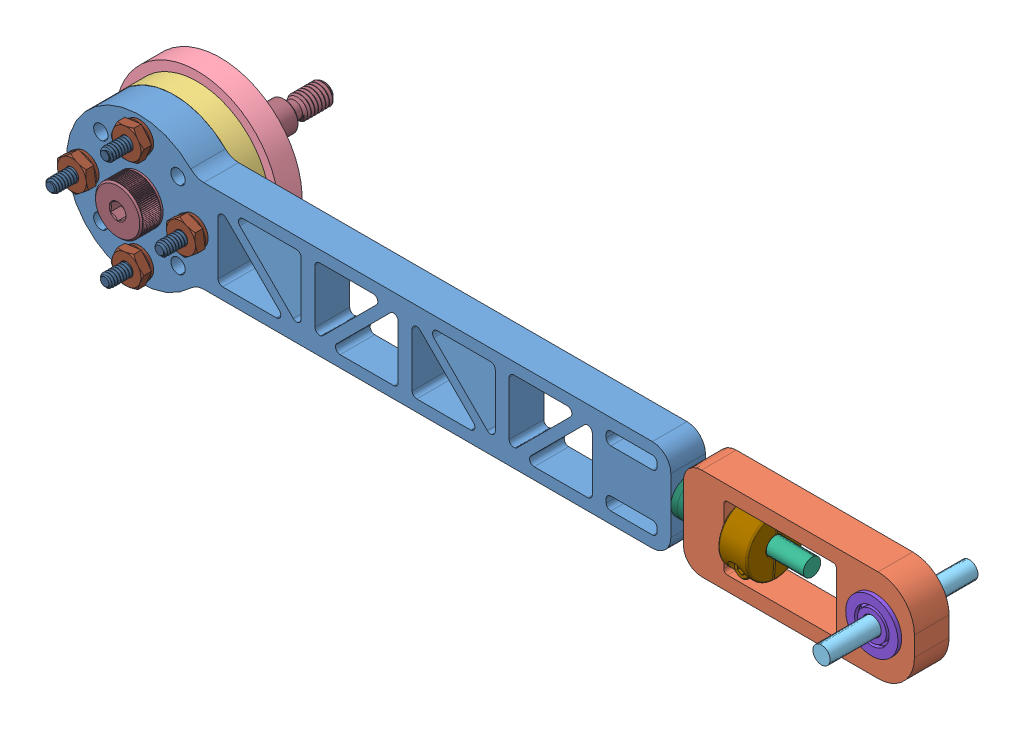
SolidWorks assembly A_5_000, configuration Default. Lengths in mm.
Overall size (235.5 45 66.17).
30 component instances, 15 part files, 41 mates.
Components (placement in the parent):
- A_5_001-1: A_5_001 [Default] at (-75.025 12.7 0) size (166.05 40 9.53)
- A_5_002-1: A_5_002 [Default] at (1.4544 0 0) size (63.5 25.4 9.53)
- A_5_003-1: A_5_003 [Default] at (-148.05 12.7 -6.35) size (40 40 6.35)
- A_5_004-1: A_5_004 [Default] at (-148.05 12.7 -6.35) x (1 0 0) z (0 0 -1) size (45 45 6.35)
- shaft-1: shaft [Default] at (54.2575 12.7 -16.2686) x (0.996155 -0.087603 0) z (0 0 1) size (4.76 4.76 40.64)
- shaft_2-1: shaft_2 [Default] at (-23.5795 12.7 4.7625) x (0 0.971236 0.23812) z (1 0 0) size (4.76 4.76 55.63)
- 2938T280-1: 2938T280 [2938T28] at (14.1481 12.7 4.7625) x (0 0.795039 -0.606559) z (0 0.606559 0.795039) size (11.11 12.7 11.11)
- 57155K302-1: 57155K302 [57155K302] at (54.2575 12.7 0.9684) x (0.999308 -0.037205 0) z (0 0 1) size (14.35 14.35 3.97)
- 57155K302-2: 57155K302 [57155K302] at (54.2575 12.7 8.5566) x (-0.923728 -0.383049 0) z (0 0 -1) size (14.35 14.35 3.97)
- 6157K310-1: 6157K310 [6157K31] at (18.1169 12.7 4.7625) x (0 -0.08236 -0.996603) z (-1 0 0) size (15.88 15.89 7.98)
- 92210A155-1: 92210A155 [92210A155] at (-148.05 27.7 -12.7) x (1 0 0) z (0 0 -1) size (7.8 7.8 32.26)
- 95170A355-1: 95170A355 [95170A355] at (-148.05 27.7 9.525) x (-0.141785 0.989897 0) z (0.989897 0.141785 0) size (8.33 3.94 9.17)
- 92373A215-1: 92373A215 [92373A215] at (-137.4434 23.3066 -3.175) size (4.08 4.11 19.05)
- 92981A206-1: 92981A206 [92981A206] at (-148.05 12.7 15.525) size (13 13 57.56)
- 98055A114-1: 98055A114 [Default] at (-148.05 12.7 -13.2) x (-0.853776 0.520641 0) z (0 0 1) size (14 14 0.5)
- 98055A114-4: 98055A114 [Default] at (-148.05 12.7 -13.7) x (0.553514 -0.83284 0) z (0 0 1) size (14 14 0.5)
- 98055A114-3: 98055A114 [Default] at (-148.05 12.7 -14.2) x (-0.496071 -0.868282 0) z (0 0 1) size (14 14 0.5)
- 98055A114-6: 98055A114 [Default] at (-148.05 12.7 -14.7) x (0.941927 -0.335817 0) z (0 0 1) size (14 14 0.5)
- 98055A114-5: 98055A114 [Default] at (-148.05 12.7 -15.2) x (0.942593 0.333943 0) z (0 0 1) size (14 14 0.5)
- 92373A215-5: 92373A215 [92373A215] at (-158.6566 23.3066 -3.175) x (0 1 0) z (0 0 1) size (4.08 4.11 19.05)
- 92373A215-6: 92373A215 [92373A215] at (-158.6566 2.0934 -3.175) x (-1 0 0) z (0 0 1) size (4.08 4.11 19.05)
- 92373A215-7: 92373A215 [92373A215] at (-137.4434 2.0934 -3.175) x (0 -1 0) z (0 0 1) size (4.08 4.11 19.05)
- 95170A355-2: 95170A355 [95170A355] at (-163.05 12.7 9.525) x (-0.989897 -0.141785 0) z (-0.141785 0.989897 0) size (8.33 3.94 9.17)
- 95170A355-3: 95170A355 [95170A355] at (-148.05 -2.3 9.525) x (0.141785 -0.989897 0) z (-0.989897 -0.141785 0) size (8.33 3.94 9.17)
- 95170A355-4: 95170A355 [95170A355] at (-133.05 12.7 9.525) x (0.989897 0.141785 0) z (0.141785 -0.989897 0) size (8.33 3.94 9.17)
- 92210A155-5: 92210A155 [92210A155] at (-163.05 12.7 -12.7) x (0 1 0) z (0 0 -1) size (7.8 7.8 32.26)
- 92210A155-6: 92210A155 [92210A155] at (-148.05 -2.3 -12.7) x (-1 0 0) z (0 0 -1) size (7.8 7.8 32.26)
- 92210A155-7: 92210A155 [92210A155] at (-133.05 12.7 -12.7) x (0 -1 0) z (0 0 -1) size (7.8 7.8 32.26)
- 90183A315-1: 90183A315 [90183A315] at (-0.2728 12.7 4.7625) x (0 0.636481 -0.771293) z (1 0 0) size (9.53 9.53 1.73)
- 90183A315-2: 90183A315 [90183A315] at (1.4544 12.7 4.7625) x (0 0 -1) z (1 0 0) size (9.53 9.53 1.73)
Mates (geometry in assembly coordinates):
- Concentric1: concentric anti-aligned: cylinder of A_5_002-1 through (64.9554 12.7 4.7625) axis (-1 0 0) radius 3.9751; cylinder of 2938T280-1 through (1.4482 12.7 4.7625) axis (1 0 0) radius 3.9751
- Coincident1: coincident anti-aligned: plane of A_5_002-1 through (12.5606 3.95 0) normal (1 0 0); plane of 2938T280-1 through (12.5606 12.7 4.7625) normal (-1 0 0)
- Concentric2: concentric aligned: cylinder of A_5_002-1 through (54.2575 12.7 0) axis (0 0 1) radius 6.35; cylinder of 57155K302-1 through (54.2575 12.7 2.9527) axis (0 0 1) radius 6.35
- Coincident2: coincident aligned: plane of A_5_002-1; circle of 57155K302-1
- Concentric3: concentric anti-aligned: cylinder of A_5_002-1 through (54.2575 12.7 0) axis (0 0 1) radius 6.35; cylinder of 57155K302-2 through (54.2575 12.7 6.5723) axis (0 0 -1) radius 6.35
- Coincident3: coincident aligned: plane of A_5_002-1; circle of 57155K302-2
- Concentric4: concentric aligned: cylinder of 57155K302-2 through (54.2575 12.7 6.5723) axis (0 0 -1) radius 2.3813; cylinder of shaft-1 through (54.2575 12.7 24.3714) axis (0 0 -1) radius 2.3813
- Concentric5: concentric anti-aligned: cylinder of 2938T280-1 through (1.4482 12.7 4.7625) axis (1 0 0) radius 2.394; cylinder of shaft_2-1 through (32.0465 12.7 4.7625) axis (-1 0 0) radius 2.3813
- Concentric7: concentric anti-aligned: cylinder of A_5_001-1 through (-168.051 12.7 4.7625) axis (1 0 0) radius 2.3813; cylinder of shaft_2-1 through (32.0465 12.7 4.7625) axis (-1 0 0) radius 2.3813
- Concentric8: concentric anti-aligned: cylinder of shaft_2-1 through (32.0465 12.7 4.7625) axis (-1 0 0) radius 2.3813; cylinder of 6157K310-1 through (14.1481 12.7 4.7625) axis (1 0 0) radius 2.3813
- Coincident4: coincident anti-aligned: plane of 2938T280-1 through (14.1481 12.7 4.7625) normal (1 0 0); plane of 6157K310-1 through (14.1481 12.7 4.7625) normal (-1 0 0)
- Coincident5: coincident aligned: plane of A_5_001-1 through (-23.5795 3.175 0) normal (-1 0 0); plane of shaft_2-1 through (-23.5795 12.7 4.7625) normal (-1 0 0)
- Concentric9: concentric aligned: cylinder of A_5_001-1 through (-148.05 12.7 9.525) axis (0 0 -1) radius 4; cylinder of A_5_003-1 through (-148.05 12.7 0) axis (0 0 -1) radius 4
- Concentric10: concentric aligned: cylinder of A_5_001-1 through (-148.05 27.7 9.525) axis (0 0 -1) radius 1.8986; cylinder of A_5_003-1 through (-148.05 27.7 0) axis (0 0 -1) radius 1.8986
- Coincident6: coincident anti-aligned: plane of A_5_001-1 through (-148.05 12.7 0) normal (0 0 -1); plane of A_5_003-1 through (-148.05 12.7 0) normal (0 0 1)
- Concentric11: concentric anti-aligned: cylinder of A_5_003-1 through (-148.05 12.7 0) axis (0 0 -1) radius 4; cylinder of A_5_004-1 through (-148.05 12.7 -12.7) axis (0 0 1) radius 4
- Concentric12: concentric anti-aligned: cylinder of A_5_003-1 through (-148.05 27.7 0) axis (0 0 -1) radius 1.8986; cylinder of A_5_004-1 through (-148.05 27.7 -12.7) axis (0 0 1) radius 1.8986
- Coincident7: coincident anti-aligned: plane of A_5_003-1 through (-148.05 12.7 -6.35) normal (0 0 -1); plane of A_5_004-1 through (-148.05 12.7 -6.35) normal (0 0 1)
- Concentric13: concentric aligned: cylinder of A_5_004-1 through (-148.05 27.7 -12.7) axis (0 0 1) radius 1.8986; circle of 92210A155-1
- Coincident8: coincident aligned: plane of A_5_004-1 through (-148.05 12.7 -12.7) normal (0 0 -1); plane of 92210A155-1 through (-148.05 27.7 -12.7) normal (0 0 -1)
- Concentric14: concentric anti-aligned: cylinder of A_5_001-1 through (-148.05 27.7 9.525) axis (0 0 -1) radius 1.8986; circle of 95170A355-1
- Coincident9: coincident anti-aligned: plane of A_5_001-1 through (-148.05 12.7 9.525) normal (0 0 1); plane of 95170A355-1 through (-152.5864 27.0502 9.525) normal (0 0 -1)
- Concentric15: concentric anti-aligned: cylinder of A_5_004-1 through (-137.4434 23.3066 -12.7) axis (0 0 1) radius 1.9939; circle of 92373A215-1
- Coincident10: coincident aligned: plane of A_5_004-1 through (-148.05 12.7 -12.7) normal (0 0 -1); plane of 92373A215-1 through (-137.4434 23.3066 -12.7) normal (0 0 -1)
- Concentric16: concentric aligned: cylinder of A_5_001-1 through (-148.05 12.7 9.525) axis (0 0 -1) radius 4; cylinder of 92981A206-1 through (-148.05 12.7 -41.475) axis (0 0 -1) radius 4
- Coincident11: coincident anti-aligned: plane of A_5_001-1 through (-148.05 12.7 9.525) normal (0 0 1); plane of 92981A206-1 through (-148.05 6.2 9.525) normal (0 0 -1)
- Concentric17: concentric anti-aligned: cylinder of A_5_004-1 through (-148.05 12.7 -12.7) axis (0 0 1) radius 4; cylinder of 98055A114-1 through (-148.05 12.7 -12.7) axis (0 0 -1) radius 4
- Coincident12: coincident anti-aligned: plane of A_5_004-1 through (-148.05 12.7 -12.7) normal (0 0 -1); plane of 98055A114-1 through (-148.05 12.7 -12.7) normal (0 0 1)
- Concentric18: concentric anti-aligned: cylinder of A_5_004-1 through (-148.05 12.7 -12.7) axis (0 0 1) radius 4; cylinder of 98055A114-4 through (-148.05 12.7 -13.2) axis (0 0 -1) radius 4
- Coincident13: coincident anti-aligned: plane of 98055A114-1 through (-148.05 12.7 -13.2) normal (0 0 -1); plane of 98055A114-4 through (-148.05 12.7 -13.2) normal (0 0 1)
- Concentric19: concentric anti-aligned: cylinder of A_5_004-1 through (-148.05 12.7 -12.7) axis (0 0 1) radius 4; cylinder of 98055A114-3 through (-148.05 12.7 -13.7) axis (0 0 -1) radius 4
- Coincident14: coincident anti-aligned: plane of 98055A114-4 through (-148.05 12.7 -13.7) normal (0 0 -1); plane of 98055A114-3 through (-148.05 12.7 -13.7) normal (0 0 1)
- Concentric20: concentric anti-aligned: cylinder of A_5_004-1 through (-148.05 12.7 -12.7) axis (0 0 1) radius 4; cylinder of 98055A114-6 through (-148.05 12.7 -14.2) axis (0 0 -1) radius 4
- Coincident15: coincident anti-aligned: plane of 98055A114-3 through (-148.05 12.7 -14.2) normal (0 0 -1); plane of 98055A114-6 through (-148.05 12.7 -14.2) normal (0 0 1)
- Concentric21: concentric anti-aligned: cylinder of A_5_004-1 through (-148.05 12.7 -12.7) axis (0 0 1) radius 4; cylinder of 98055A114-5 through (-148.05 12.7 -14.7) axis (0 0 -1) radius 4
- Coincident16: coincident anti-aligned: plane of 98055A114-6 through (-148.05 12.7 -14.7) normal (0 0 -1); plane of 98055A114-5 through (-148.05 12.7 -14.7) normal (0 0 1)
- Concentric22: concentric anti-aligned: cylinder of shaft_2-1 through (32.0465 12.7 4.7625) axis (-1 0 0) radius 2.3813; cylinder of 90183A315-1 through (-2 12.7 4.7625) axis (1 0 0) radius 2.4384
- Coincident18: coincident anti-aligned: plane of A_5_001-1 through (-2 25.4 9.525) normal (1 0 0); plane of 90183A315-1 through (-2 12.7 4.7625) normal (-1 0 0)
- Concentric23: concentric anti-aligned: cylinder of shaft_2-1 through (32.0465 12.7 4.7625) axis (-1 0 0) radius 2.3813; cylinder of 90183A315-2 through (-0.2728 12.7 4.7625) axis (1 0 0) radius 2.4384
- Coincident19: coincident anti-aligned: plane of 90183A315-1 through (-0.2728 12.7 4.7625) normal (1 0 0); plane of 90183A315-2 through (-0.2728 12.7 4.7625) normal (-1 0 0)
- Coincident20: coincident anti-aligned: plane of A_5_002-1 through (1.4544 0 9.525) normal (-1 0 0); plane of 90183A315-2 through (1.4544 12.7 4.7625) normal (1 0 0)
